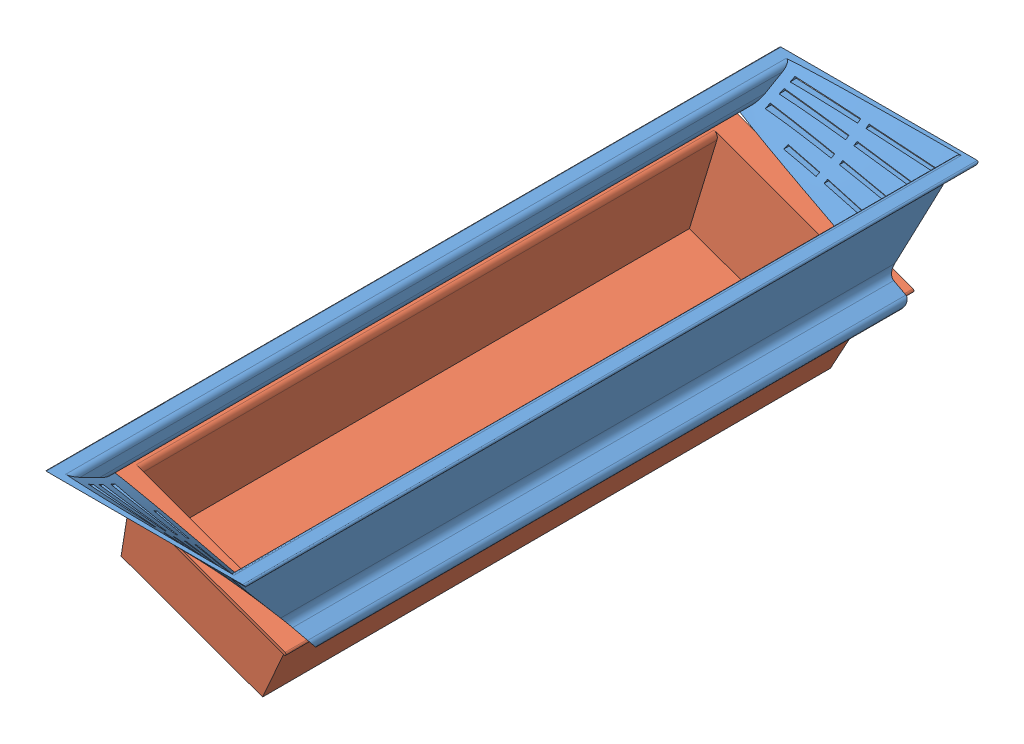
SolidWorks assembly Assemblage rehausse et panier 2026, configuration Défaut. Lengths in mm.
Overall size (134.86 104.96 439.83).
2 component instances, 2 part files, 1 mates.
Components (placement in the parent):
- rallonge pour pannier a Pollen modification 2026-1: rallonge pour pannier a Pollen modification 2026 [Défaut] at (15.3591 126.4137 659.5781) size (119.29 55.99 439.83)
- panier a pollen-1: panier a pollen [Défaut] at (-2.4041 -29.9087 441.7394) x (-0.001028 0.000374 -0.999999) z (0.939692 -0.34202 -0.001094) size (376 55.75 118)
Mates (geometry in assembly coordinates):
- Distance1: distance = 1 mm anti-aligned: plane of panier a pollen-1 through (58.1343 -17.4349 616.6819) normal (0.34202 0.939693 0); plane of rallonge pour pannier a Pollen modification 2026-1 through (-25.5272 14.0795 220.0781) normal (-0.34202 -0.939693 0)
